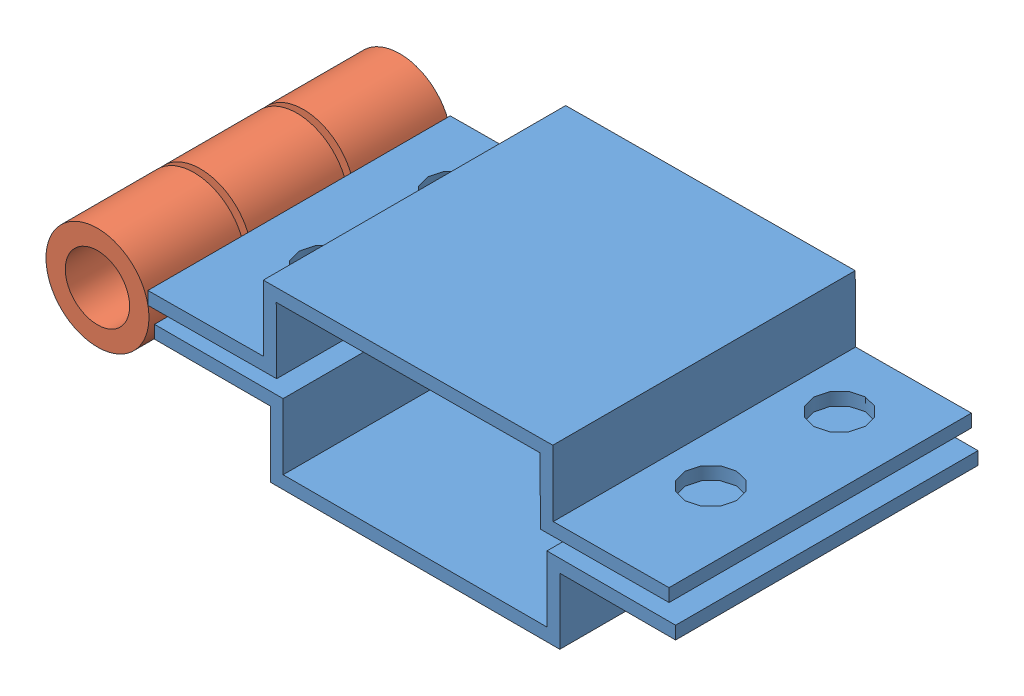
SolidWorks assembly МуфтаМ, configuration По умолчанию. Lengths in mm.
Overall size (99.44 71.98 48).
7 component instances, 2 part files, 2 mates.
Components (placement in the parent):
- СкобаМ2-1: СкобаМ2 [По умолчанию] at (133.343 0 0) x (-1 0 0) z (0 0 1) size (99.31 57.49 47)
  - Скоба-1: Скоба [По умолчанию] at (68.8429 -12.25 0) x (0 0 -1) z (1 0 0) size (47 57.49 81)
  - Втулка-1: Втулка [По умолчанию] at (117.2011 -13.75 -15) x (-0.923728 -0.383049 0) z (0.383049 -0.923728 0) size (16 15 16)
- СкобаМ1-1: СкобаМ1 [По умолчанию] at (64.4899 15.5461 -46) x (0 0 1) z (-0.999981 -0.006123 0) size (47 57.49 98.28)
  - Скоба-1: Скоба [По умолчанию] at origin size (47 57.49 81)
  - Втулка-3: Втулка [По умолчанию] at (32 -1.5 48.3581) x (0 0.980296 -0.197536) z (0 -0.197536 -0.980296) size (16 15 16)
  - Втулка-4: Втулка [По умолчанию] at (0 -1.5 48.3581) x (0 0.980296 -0.197536) z (0 -0.197536 -0.980296) size (16 15 16)
Mates (geometry in assembly coordinates):
- Концентричный1: concentric anti-aligned: cylinder of СкобаМ2-1/Втулка-1 through (16.1419 13.75 -30) axis (0 0 1) radius 5; cylinder of СкобаМ1-1/Втулка-4 through (16.1419 13.75 -31) axis (0 0 -1) radius 5
- Расстояние1: distance = 1 mm anti-aligned: plane of СкобаМ2-1/Втулка-1 through (16.1419 13.75 -30) normal (0 0 -1); plane of СкобаМ1-1/Втулка-4 through (16.1419 13.75 -31) normal (0 0 1)
